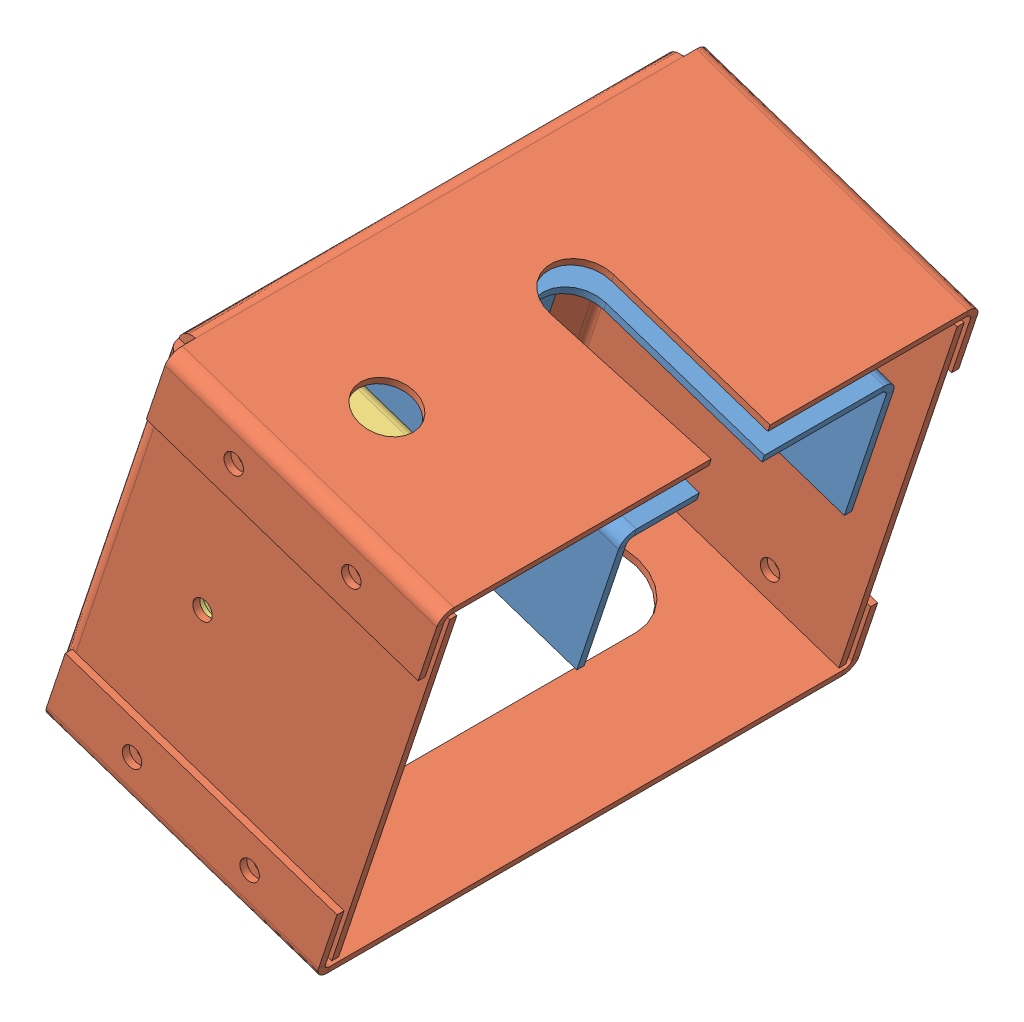
SolidWorks assembly motorbox Assembly, configuration Default. Lengths in mm.
Overall size (50.54 58.37 88.68).
3 component instances, 3 part files, 5 mates.
Components (placement in the parent):
- Motor Fixture-1: Motor Fixture [Default] at (-47.7174 -16.0513 13.8192) x (-0.316256 -0.948674 0) z (0 0 1) size (43 36.41 33.82)
- Motor Gear Box V2-1: Motor Gear Box V2 [Default] at (-55.1911 -35.5927 4.6469) x (-0.316256 -0.948674 0) z (0 0 1) size (49.24 36.86 66.49)
- encoder holder-1: encoder holder [Default] at (-55.2728 -38.557 25.4269) x (0 0 -1) z (-0.316256 -0.948674 0) size (19.96 20.86 30.86)
Mates (geometry in assembly coordinates):
- Coincident6: coincident aligned: line of Motor Fixture-1 through (-49.1095 -17.3497 13.8192) axis (0 0 -1)
- Coincident7: coincident anti-aligned: plane of Motor Fixture-1 through (-48.5807 -15.7635 13.8192) normal (-0.948674 0.316256 0); plane of Motor Gear Box V2-1 through (-55.1911 -35.5927 4.6469) normal (0.948674 -0.316256 0)
- Coincident8: coincident anti-aligned: plane of Motor Gear Box V2-1 through (-55.1911 -35.5927 4.6469) normal (0.948674 -0.316256 0); plane of encoder holder-1 through (-56.0886 -38.285 25.4269) normal (-0.948674 0.316256 0)
- Coincident10: coincident anti-aligned: plane of Motor Gear Box V2-1 through (-55.1911 -35.5927 35.4089) normal (0 0 -1); plane of encoder holder-1 through (-55.2728 -38.557 35.4089) normal (0 0 1)
- Coincident11: coincident anti-aligned: line of encoder holder-1 through (-51.5858 -24.7778 32.1649) axis (0 0 -1)
